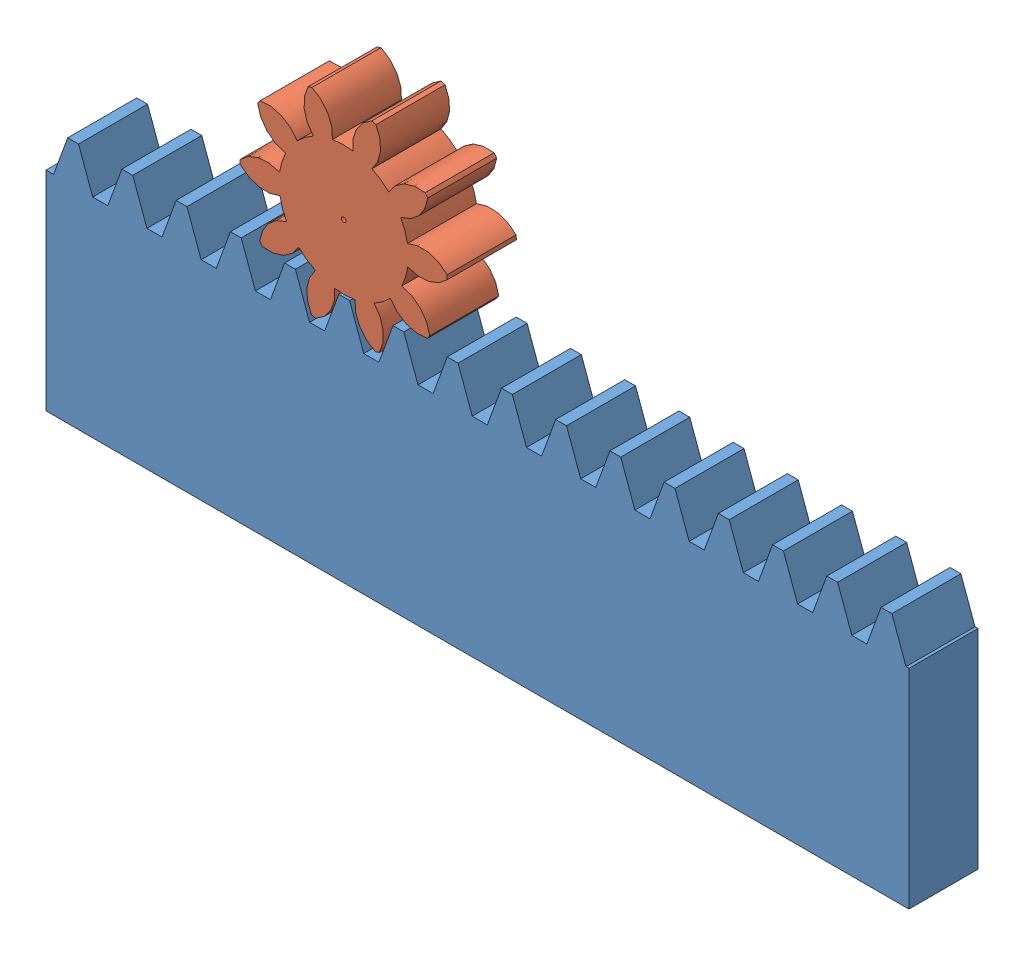
SolidWorks assembly Assem1, configuration Default. Lengths in mm.
Overall size (150 72.21 12).
2 component instances, 2 part files, 1 mates.
Components (placement in the parent):
- rack spur rectangular_am-1: rack spur rectangular_am [Metric - Rack-spur - rectangular 3M 20PA 12FW 40PH 150L---SAll] at (-93.5985 -25.7524 18.7032) size (150 43 12)
- spur gearj_am-1: spur gearj_am [Metric - Spur gear 3M 10T 20PA 12FW ---S10N75H50L0.8N] at (-41.8529 28.9175 18.7032) x (0 0 -1) z (0.999846 0.017572 0) size (12 34.46 36)
Mates (geometry in assembly coordinates):
- Parallel1: parallel aligned: plane of rack spur rectangular_am-1 through (-93.5985 17.2476 18.7032) normal (0 0 1); plane of spur gearj_am-1 through (-41.8529 28.9175 18.7032) normal (0 0 1)
